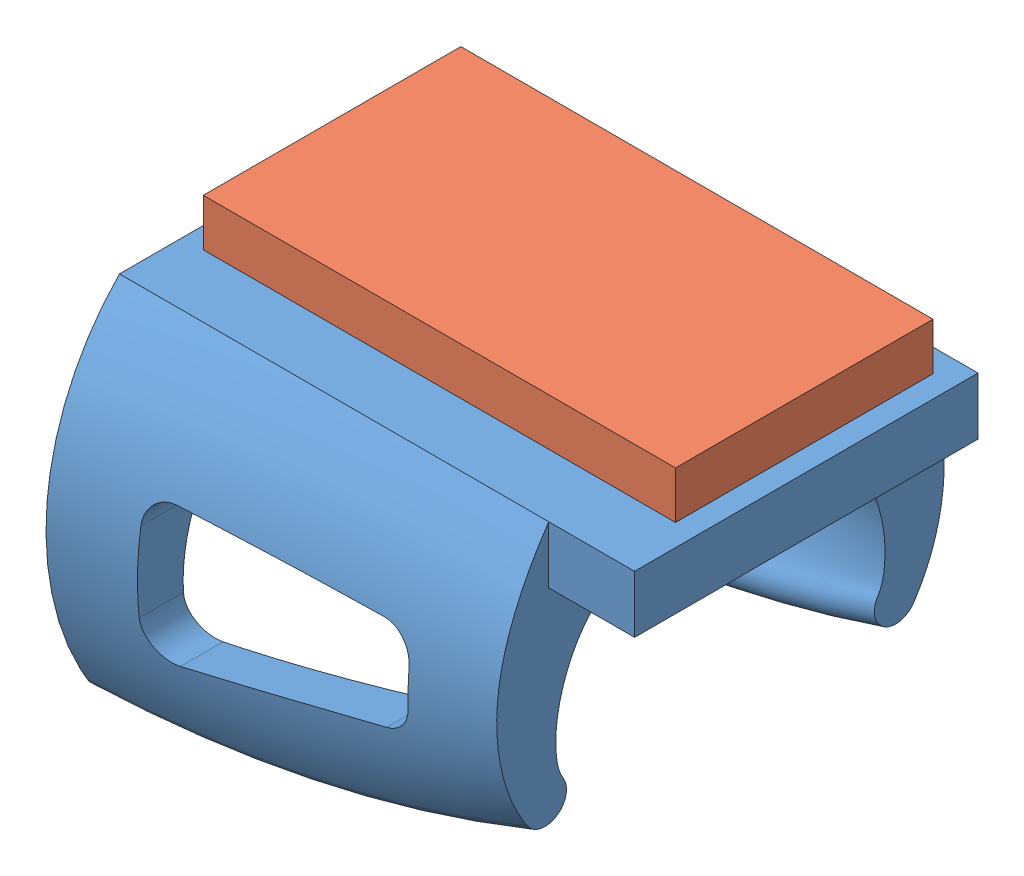
SolidWorks assembly IMUglove_AssemColin_v1, configuration Default. Lengths in mm.
Overall size (18.01 14.52 17.41).
2 component instances, 2 part files, 0 mates.
Components (placement in the parent):
- IMURing_DistalColin_v1-1: IMURing_DistalColin_v1 [Default] at (-78.4007 40.3316 12.7639) size (18.01 12.12 17.41)
- IMUwear_v1-1: IMUwear_v1 [Default] at (-68.6548 43.0915 12.8297) size (16.5 1.65 9)
